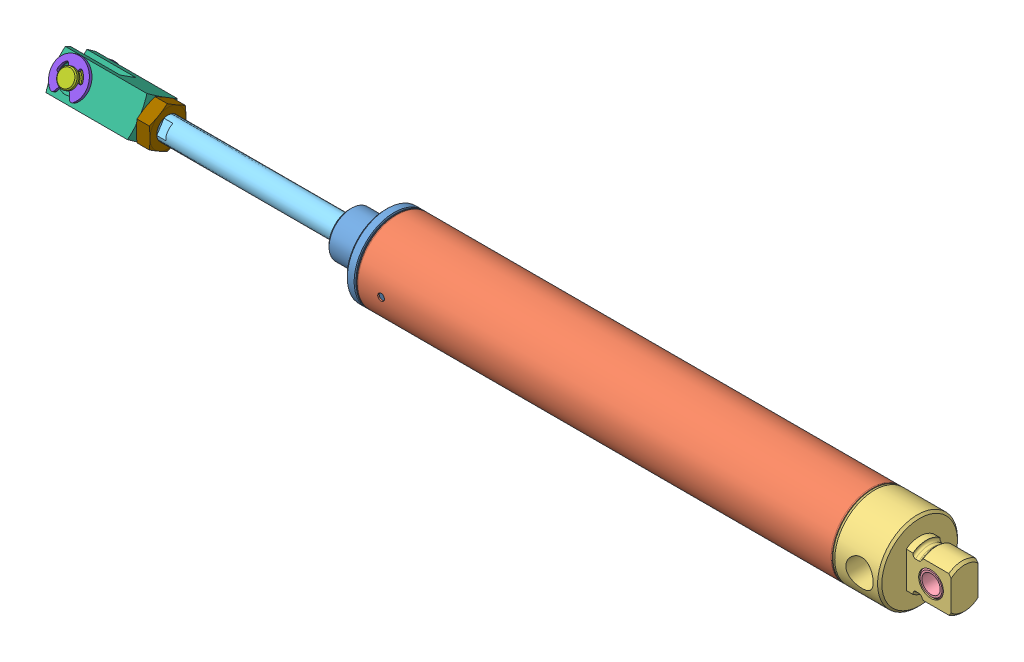
SolidWorks assembly 093_5-PY(F,D-166-1), configuration Default. Lengths in mm.
Overall size (317.17 37.46 37.46).
12 component instances, 11 part files, 28 mates.
Components (placement in the parent):
- 093_5-PCY(F,D-166-1)0000_0_dummy-1: 093_5-PCY(F,D-166-1)0000_0_dummy [Default] at origin
- 09000-0_rod_guide-1: 09000-0_rod_guide [Default] at origin size (25.4 28.27 28.27)
- 09-6_6212C-1: 09-6_6212C [Default] at (16.637 0 0) size (169.53 28.27 28.27)
- 09P0Y000_rear_head-1: 09P0Y000_rear_head [Default] at (179.2224 0 0) size (38.1 28.22 28.22)
- D-3543-1: D-3543 [Default] at (210.185 0 0) x (1 0 0) z (0 0 -1) size (8.78 8.78 9.4)
- C-093_5-PY0_rod-1: C-093_5-PY0_rod [Default] at (-60.8125 0 0) x (1 0 0) z (0 0.539181 0.84219) size (195.1 27.11 27.11)
- D-166-1-dummy-1: D-166-1-dummy [Default] at (-92.6387 0 0) x (1 0 0) z (0 0.539181 0.84219)
- D-14059-1: D-14059 [Default] at (-92.6387 0 0) x (1 0 0) z (0 -0.539181 -0.84219) size (31.89 12.7 12.7)
- D-8381-1: D-8381 [Default] at (-92.6387 0 0) x (0 0.539181 0.84219) z (-1 0 0) size (17.53 6.35 6.35)
- D-5866-1: D-5866 [Default] at (-92.6387 3.7491 5.856) x (-1 0 0) z (0 -0.539181 -0.84219) size (12.7 11.45 1.1)
- D-5866-2: D-5866 [Default] at (-92.6387 -3.7491 -5.856) x (-1 0 0) z (0 -0.539181 -0.84219) size (12.7 11.45 1.1)
- D-746-1: D-746 [Default] at (-68.8135 0 0) x (0 0 1) z (-1 0 0) size (12.7 14.66 4.83)
Mates (geometry in assembly coordinates):
- Distance2: distance = 0 mm aligned: plane of 09000-0_rod_guide-1 through (0 0 0) normal (1 0 0); plane of 093_5-PCY(F,D-166-1)0000_0_dummy-1 through (0 0 0) normal (1 0 0)
- Coincident1: coincident aligned: line of 093_5-PCY(F,D-166-1)0000_0_dummy-1 through (80.9 0 0) axis (-1 0 0); line of 09000-0_rod_guide-1 through (80.9 0 0) axis (-1 0 0)
- Angle3: planar angle = 0 rad aligned: plane of 09000-0_rod_guide-1 through (0 0 0) normal (0 0 -1); plane of 093_5-PCY(F,D-166-1)0000_0_dummy-1 through (0 0 0) normal (0 0 -1)
- Distance4: distance = 0 mm aligned: plane of 09-6_6212C-1 through (16.637 0 0) normal (1 0 0); plane of 09000-0_rod_guide-1 through (16.637 0 0) normal (1 0 0)
- Coincident2: coincident aligned: line of 09000-0_rod_guide-1 through (80.9 0 0) axis (-1 0 0); line of 09-6_6212C-1 through (97.537 0 0) axis (-1 0 0)
- Angle6: planar angle = 0 rad aligned: plane of 09-6_6212C-1 through (16.637 0 0) normal (0 0 -1); plane of 09000-0_rod_guide-1 through (0 0 0) normal (0 0 -1)
- Distance6: distance = 0 mm aligned: plane of 09P0Y000_rear_head-1 through (184.8104 0 0) normal (1 0 0); plane of 09-6_6212C-1 through (184.8104 0 0) normal (1 0 0)
- Coincident3: coincident aligned: line of 09-6_6212C-1 through (97.537 0 0) axis (-1 0 0); line of 09P0Y000_rear_head-1 through (260.1224 0 0) axis (-1 0 0)
- Angle9: planar angle = 0.000031 rad aligned: plane of 09P0Y000_rear_head-1 through (179.2224 0 0) normal (0 0 -1); plane of 09-6_6212C-1 through (16.637 0 0) normal (0 0 -1)
- Distance7: distance = 0 mm anti-aligned: plane of D-3543-1 through (210.185 0 0) normal (0 0 -1); plane of 09P0Y000_rear_head-1 through (179.2224 0 0) normal (0 0 1)
- Coincident4: coincident anti-aligned: line of 09P0Y000_rear_head-1 through (210.185 0 80.9) axis (0 0 -1); line of D-3543-1 through (210.185 0 -80.9) axis (0 0 1)
- Angle12: planar angle = 0 rad aligned: plane of D-3543-1; plane of 09P0Y000_rear_head-1 through (210.185 0 0) normal (1 0 0)
- LimitDistance2: limit distance = 60.8125 mm aligned: plane of C-093_5-PY0_rod-1; plane of 09000-0_rod_guide-1 through (0 0 0) normal (1 0 0)
- Coincident5: coincident aligned: line of 09000-0_rod_guide-1 through (80.9 0 0) axis (-1 0 0); line of C-093_5-PY0_rod-1 through (20.0875 0 0) axis (-1 0 0)
- Distance9: distance = 0 mm aligned: plane of D-166-1-dummy-1; plane of C-093_5-PY0_rod-1
- Coincident6: coincident aligned: line of C-093_5-PY0_rod-1 through (20.0875 0 0) axis (-1 0 0); line of D-166-1-dummy-1 through (-11.7387 0 0) axis (-1 0 0)
- Angle15: planar angle = 0 rad aligned: plane of D-166-1-dummy-1; plane of C-093_5-PY0_rod-1
- Distance10: distance = 0 mm anti-aligned: plane of D-14059-1 through (-92.6387 0 0) normal (0 -0.539181 -0.84219); plane of D-166-1-dummy-1 through (-92.6387 0 0) normal (0 0.539181 0.84219)
- Coincident7: coincident anti-aligned: line of D-166-1-dummy-1 through (-92.6387 43.6198 68.1331) axis (0 -0.539181 -0.84219); line of D-14059-1 through (-92.6387 -43.6198 -68.1331) axis (0 0.539181 0.84219)
- Angle18: planar angle = 0 rad aligned: plane of D-14059-1; plane of D-166-1-dummy-1
- Coincident8: coincident anti-aligned: plane of D-14059-1 through (-92.6387 0 0) normal (0 -0.539181 -0.84219); plane of D-8381-1
- Coincident9: coincident anti-aligned: line of D-14059-1 through (-92.6387 -43.6198 -68.1331) axis (0 0.539181 0.84219); line of D-8381-1 through (-92.6387 43.6198 68.1331) axis (0 -0.539181 -0.84219)
- Coincident10: coincident anti-aligned: plane of D-8381-1; plane of D-5866-1 through (-92.6387 3.7491 5.856) normal (0 -0.539181 -0.84219)
- Coincident11: coincident anti-aligned: line of D-8381-1 through (-92.6387 43.6198 68.1331) axis (0 -0.539181 -0.84219); line of D-5866-1 through (-92.6387 -39.8707 -62.2772) axis (0 0.539181 0.84219)
- Coincident12: coincident anti-aligned: plane of D-8381-1; plane of D-5866-2 through (-92.6387 -3.7491 -5.856) normal (0 -0.539181 -0.84219)
- Coincident13: coincident anti-aligned: line of D-8381-1 through (-92.6387 43.6198 68.1331) axis (0 -0.539181 -0.84219); line of D-5866-2 through (-92.6387 -47.3688 -73.9891) axis (0 0.539181 0.84219)
- Coincident14: coincident anti-aligned: plane of D-14059-1; plane of D-746-1 through (-68.8135 0 0) normal (-1 0 0)
- Coincident15: coincident anti-aligned: line of D-14059-1 through (-11.7387 0 0) axis (-1 0 0); line of D-746-1 through (-149.7135 0 0) axis (1 0 0)
